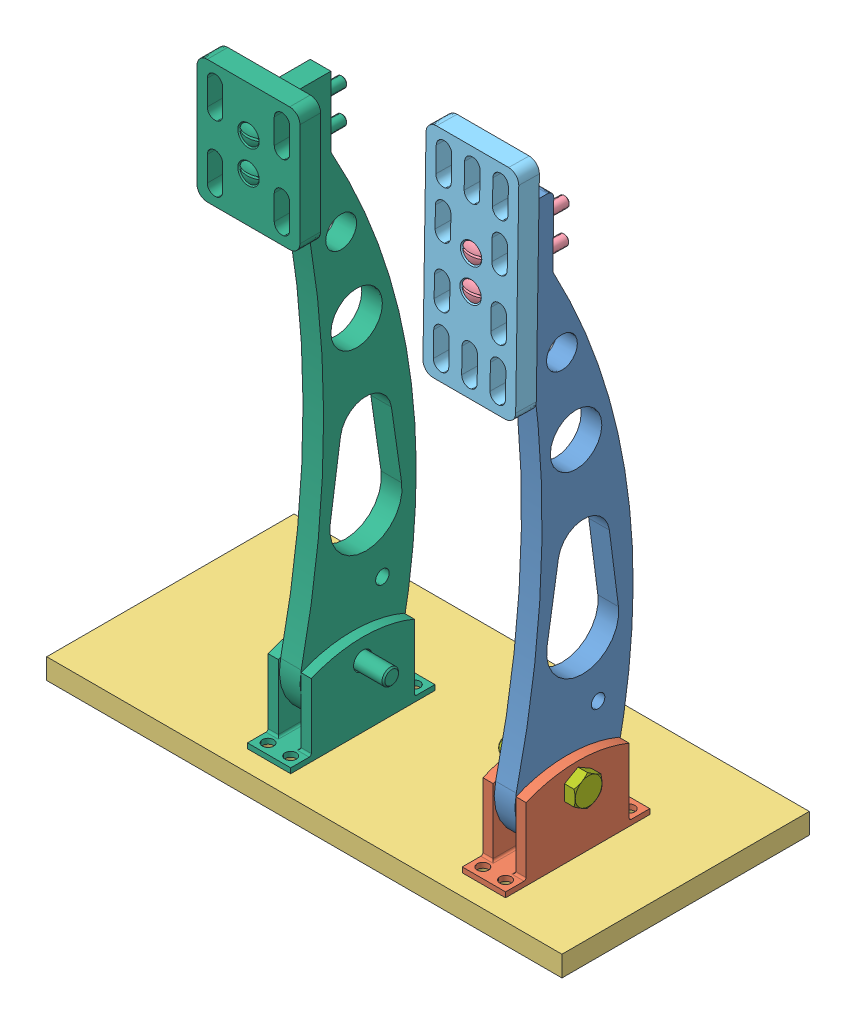
SolidWorks assembly Pedal Box Final Assembly, configuration Default. Lengths in mm.
Overall size (250 325.08 125.22).
9 component instances, 7 part files, 13 mates.
Components (placement in the parent):
- Assem1-1: Assem1 [Default] at (125.4355 289.6926 59.207) x (1 0 0) z (0 0.015835 0.999875) size (250 290.71 120.14)
  - Pedal support-1: Pedal support [Default] at (-54.204 -249.8959 -11.4765) x (-1 0 0) z (0 0 -1) size (10 275 71.45)
  - Base Pedal Interface-1: Base Pedal Interface [Default] at (-69.9575 -279.4963 -36.9484) x (1 0 0) z (0 -0.015835 0.999875) size (21 40 70)
  - Base-1: Base [Default] at (-261.3296 -290.6035 32.8844) x (1 0 0) z (0 -0.015835 0.999875) size (250 10 120)
- din_en_iso2010_m5x45_4_8-1: din_en_iso2010_m5x45_4_8 [Default] at (66.2477 278.3395 93.5761) x (-1 -0.000138 0.000002) z (0 -0.015835 -0.999875) size (9.22 9.3 46.18)
- din_en_iso2010_m5x45_4_8-2: din_en_iso2010_m5x45_4_8 [Default] at (66.2477 262.3415 93.8294) x (-1 0.000968 -0.000015) z (0 -0.015835 -0.999875) size (9.22 9.3 46.18)
- Accellerator Pedal-1: Accellerator Pedal [Default] at (43.7477 217.6783 83.8739) x (1 0 0) z (0 0.015835 0.999875) size (45 105 10)
- Brake pedal assembly-1: Brake pedal assembly [Default] at (-51.1948 166.1795 67.452) x (-1 0 0) z (0 0 -1) size (50 290 82.09)
- din_en_24017_m8x35-1: din_en_24017_m8x35 [Default] at (76.7315 39.6463 51.689) x (0 0 1) z (-1 0 0) size (13 15.01 40.3)
Mates (geometry in assembly coordinates):
- Concentric1: concentric aligned: cylinder of Assem1-1/Pedal support-1 through (66.2477 278.1707 82.9159) axis (0 0.015835 0.999875) radius 2.75; cylinder of din_en_iso2010_m5x45_4_8-1 through (66.2477 278.3395 93.5761) axis (0 0.015835 0.999875) radius 2.5
- Coincident1: coincident: cone of ? through (86.3228 283.6701 92.8301) axis (0 -0.015835 -0.999875); circle of din_en_iso2010_m5x45_4_8-1
- Concentric2: concentric aligned: cylinder of Assem1-1/Pedal support-1 through (66.2477 262.1727 83.1693) axis (0 0.015835 0.999875) radius 2.75; cylinder of din_en_iso2010_m5x45_4_8-2 through (66.2477 262.3415 93.8294) axis (0 0.015835 0.999875) radius 2.5
- Coincident2: coincident: cone of ? through (86.3228 267.6721 93.0834) axis (0 -0.015835 -0.999875); circle of din_en_iso2010_m5x45_4_8-2
- Concentric3: concentric aligned: cylinder of din_en_iso2010_m5x45_4_8-1 through (66.2477 278.3395 93.5761) axis (0 0.015835 0.999875) radius 2.5; cylinder of Accellerator Pedal-1 through (66.2477 278.329 92.9147) axis (0 0.015835 0.999875) radius 2.75
- Coincident3: coincident anti-aligned: plane of Assem1-1/Pedal support-1 through (61.2315 249.0723 83.3767) normal (0 0.015835 0.999875); plane of Accellerator Pedal-1 through (43.7477 217.6783 83.8739) normal (0 -0.015835 -0.999875)
- Concentric4: concentric aligned: cylinder of din_en_iso2010_m5x45_4_8-2 through (66.2477 262.3415 93.8294) axis (0 0.015835 0.999875) radius 2.5; circle of Accellerator Pedal-1
- Coincident4: coincident: circle of din_en_iso2010_m5x45_4_8-2; cone of Accellerator Pedal-1 through (66.2477 262.331 93.168) axis (0 -0.015835 -0.999875)
- Concentric5: concentric aligned: circle of Assem1-1/Base-1; circle of Brake pedal assembly-1
- Concentric6: concentric aligned: circle of Assem1-1/Base-1; circle of Brake pedal assembly-1
- Coincident5: coincident anti-aligned: plane of Assem1-1/Base-1 through (-135.894 9.6463 96.689) normal (0 1 0); plane of Brake pedal assembly-1 through (-27.5196 9.6463 26.689) normal (0 -1 0)
- Concentric7: concentric: cylinder of Assem1-1/Pedal support-1 through (61.2315 39.6463 51.689) axis (-1 0 0) radius 4.5; cylinder of din_en_24017_m8x35-1 through (77.3815 39.6463 51.689) axis (1 0 0) radius 4
- Coincident6: coincident anti-aligned: plane of Assem1-1/Base Pedal Interface-1 through (76.7315 59.6463 76.689) normal (1 0 0); plane of din_en_24017_m8x35-1 through (76.7315 44.0463 51.689) normal (-1 0 0)
